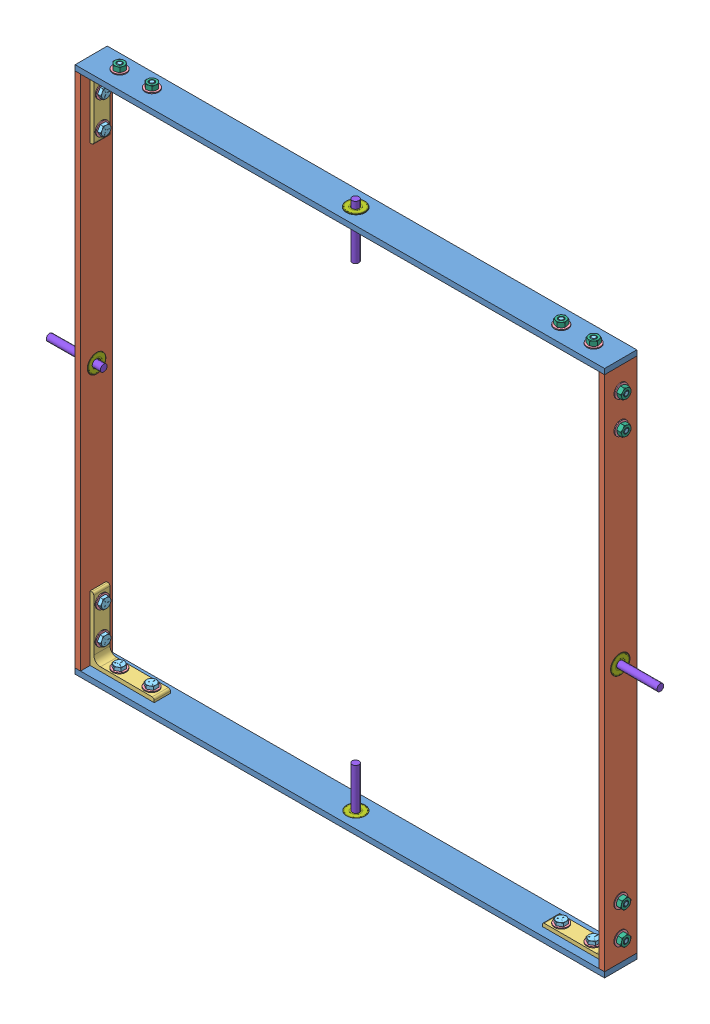
SolidWorks assembly OutR_22mm, configuration Default. Lengths in mm.
Overall size (717.82 639.44 40.05).
80 component instances, 8 part files, 23 mates.
Components (placement in the parent):
- OutR_L_22mm-1: OutR_L_22mm [Default] at (0.2194 -311.15 0.7559) x (0.999995 0 -0.003135) z (0.003135 0 0.999995) size (622.3 6.35 38.1)
- OutR_L_22mm-2: OutR_L_22mm [Default] at (0.2194 311.15 0.7559) x (-0.999995 0 0.003135) z (0.003135 0 0.999995) size (622.3 6.35 38.1)
- OutR_S_22mm-1: OutR_S_22mm [Default] at (-304.5791 0 1.7116) x (0 1 0) z (0.003135 0 0.999995) size (609.6 6.35 38.1)
- OutR_S_22mm-2: OutR_S_22mm [Default] at (305.0179 0 -0.1998) x (0 -1 0) z (0.003135 0 0.999995) size (609.6 6.35 38.1)
- Stand_Bracket_3in-1: Stand_Bracket_3in [8982K254] at (266.9181 266.7 -0.0803) x (0.999995 0 -0.003135) z (-0.003135 0 -0.999995) size (76.2 76.2 19.05)
- Stand_Bracket_3in-2: Stand_Bracket_3in [8982K254] at (-266.7 266.9181 -0.0803) x (0 0.999995 -0.003135) z (0 -0.003135 -0.999995) size (76.2 76.2 19.05)
- Stand_Bracket_3in-3: Stand_Bracket_3in [8982K254] at (-266.9181 -266.7 -0.0803) x (-0.999995 0 -0.003135) z (0.003135 0 -0.999995) size (76.2 76.2 19.05)
- Stand_Bracket_3in-4: Stand_Bracket_3in [8982K254] at (266.7 -266.9181 -0.0803) x (0 -0.999995 -0.003135) z (0 0.003135 -0.999995) size (76.2 76.2 19.05)
- 90107A029_316 Stainless Steel Washer-1: 90107A029_316 Stainless Steel Washer [90107A029] at (241.5182 298.9453 -0.0007) size (15.88 1.09 15.88)
- 92965A540_Black-Oxide Grade 5 Steel Hex Head Screws-1: 92965A540_Black-Oxide Grade 5 Steel Hex Head Screws [92965A540] at (241.5182 306.4859 -0.0007) x (0 1 0) z (-0.999784 0 0.020761) size (23.49 12.83 11.11)
- 95462A029_Medium-Strength Steel Hex Nut-1: 95462A029_Medium-Strength Steel Hex Nut [95462A029] at (241.5182 315.0203 -0.0007) x (0.295019 0 -0.955491) z (0 1 0) size (11.11 12.83 6.51)
- 90107A029_316 Stainless Steel Washer-2: 90107A029_316 Stainless Steel Washer [90107A029] at (241.5182 311.15 -0.0007) size (15.88 1.09 15.88)
- 90107A029_316 Stainless Steel Washer-3: 90107A029_316 Stainless Steel Washer [90107A029] at (279.618 311.15 -0.1201) size (15.88 1.09 15.88)
- 95462A029_Medium-Strength Steel Hex Nut-2: 95462A029_Medium-Strength Steel Hex Nut [95462A029] at (279.618 315.0203 -0.1201) x (0.295019 0 -0.955491) z (0 1 0) size (11.11 12.83 6.51)
- 92965A540_Black-Oxide Grade 5 Steel Hex Head Screws-2: 92965A540_Black-Oxide Grade 5 Steel Hex Head Screws [92965A540] at (279.618 306.4859 -0.1201) x (0 1 0) z (-0.999784 0 0.020761) size (23.49 12.83 11.11)
- 90107A029_316 Stainless Steel Washer-4: 90107A029_316 Stainless Steel Washer [90107A029] at (279.618 298.9453 -0.1201) size (15.88 1.09 15.88)
- 90107A029_316 Stainless Steel Washer-5: 90107A029_316 Stainless Steel Washer [90107A029] at (299.1632 241.3 -0.1814) x (0.00001 0.999995 0.003135) z (-0.003135 0.003135 -0.99999) size (15.88 1.09 15.88)
- 92965A540_Black-Oxide Grade 5 Steel Hex Head Screws-3: 92965A540_Black-Oxide Grade 5 Steel Hex Head Screws [92965A540] at (306.7038 241.3 -0.2051) x (0.999995 0 -0.003135) z (-0.000055 0.999845 -0.017626) size (23.49 12.83 11.11)
- 95462A029_Medium-Strength Steel Hex Nut-3: 95462A029_Medium-Strength Steel Hex Nut [95462A029] at (315.2392 241.3 -0.2318) x (-0.002993 0.298014 -0.954557) z (-0.999995 0 0.003135) size (11.11 12.83 6.51)
- 90107A029_316 Stainless Steel Washer-6: 90107A029_316 Stainless Steel Washer [90107A029] at (311.3679 241.3 -0.2197) x (0.00001 0.999995 0.003135) z (-0.003135 0.003135 -0.99999) size (15.88 1.09 15.88)
- 90107A029_316 Stainless Steel Washer-7: 90107A029_316 Stainless Steel Washer [90107A029] at (311.3679 279.4 -0.2197) x (0.00001 0.999995 0.003135) z (-0.003135 0.003135 -0.99999) size (15.88 1.09 15.88)
- 95462A029_Medium-Strength Steel Hex Nut-4: 95462A029_Medium-Strength Steel Hex Nut [95462A029] at (315.2392 279.4 -0.2318) x (-0.002993 0.298014 -0.954557) z (-0.999995 0 0.003135) size (11.11 12.83 6.51)
- 92965A540_Black-Oxide Grade 5 Steel Hex Head Screws-4: 92965A540_Black-Oxide Grade 5 Steel Hex Head Screws [92965A540] at (306.7038 279.4 -0.2051) x (0.999995 0 -0.003135) z (-0.000055 0.999845 -0.017626) size (23.49 12.83 11.11)
- 90107A029_316 Stainless Steel Washer-8: 90107A029_316 Stainless Steel Washer [90107A029] at (299.1632 279.4 -0.1814) x (0.00001 0.999995 0.003135) z (-0.003135 0.003135 -0.99999) size (15.88 1.09 15.88)
- 90107A029_316 Stainless Steel Washer-9: 90107A029_316 Stainless Steel Washer [90107A029] at (-241.3 299.1632 -0.1814) x (-0.999995 0.00001 0.003135) z (-0.003135 -0.003135 -0.99999) size (15.88 1.09 15.88)
- 90107A029_316 Stainless Steel Washer-10: 90107A029_316 Stainless Steel Washer [90107A029] at (-299.1632 -241.3 -0.1814) x (-0.00001 -0.999995 0.003135) z (0.003135 -0.003135 -0.99999) size (15.88 1.09 15.88)
- 90107A029_316 Stainless Steel Washer-11: 90107A029_316 Stainless Steel Washer [90107A029] at (241.3 -299.1632 -0.1814) x (0.999995 -0.00001 0.003135) z (0.003135 0.003135 -0.99999) size (15.88 1.09 15.88)
- 92965A540_Black-Oxide Grade 5 Steel Hex Head Screws-5: 92965A540_Black-Oxide Grade 5 Steel Hex Head Screws [92965A540] at (-241.3 306.7038 -0.2051) x (0 0.999995 -0.003135) z (-0.999845 -0.000055 -0.017626) size (23.49 12.83 11.11)
- 92965A540_Black-Oxide Grade 5 Steel Hex Head Screws-6: 92965A540_Black-Oxide Grade 5 Steel Hex Head Screws [92965A540] at (-306.7038 -241.3 -0.2051) x (-0.999995 0 -0.003135) z (0.000055 -0.999845 -0.017626) size (23.49 12.83 11.11)
- 92965A540_Black-Oxide Grade 5 Steel Hex Head Screws-7: 92965A540_Black-Oxide Grade 5 Steel Hex Head Screws [92965A540] at (241.3 -306.7038 -0.2051) x (0 -0.999995 -0.003135) z (0.999845 0.000055 -0.017626) size (23.49 12.83 11.11)
- 95462A029_Medium-Strength Steel Hex Nut-5: 95462A029_Medium-Strength Steel Hex Nut [95462A029] at (-241.3 315.2392 -0.2318) x (-0.298014 -0.002993 -0.954557) z (0 -0.999995 0.003135) size (11.11 12.83 6.51)
- 95462A029_Medium-Strength Steel Hex Nut-6: 95462A029_Medium-Strength Steel Hex Nut [95462A029] at (-315.2392 -241.3 -0.2318) x (0.002993 -0.298014 -0.954557) z (0.999995 0 0.003135) size (11.11 12.83 6.51)
- 95462A029_Medium-Strength Steel Hex Nut-7: 95462A029_Medium-Strength Steel Hex Nut [95462A029] at (241.3 -315.2392 -0.2318) x (0.298014 0.002993 -0.954557) z (0 0.999995 0.003135) size (11.11 12.83 6.51)
- 90107A029_316 Stainless Steel Washer-12: 90107A029_316 Stainless Steel Washer [90107A029] at (-241.3 311.3679 -0.2197) x (-0.999995 0.00001 0.003135) z (-0.003135 -0.003135 -0.99999) size (15.88 1.09 15.88)
- 90107A029_316 Stainless Steel Washer-13: 90107A029_316 Stainless Steel Washer [90107A029] at (-311.3679 -241.3 -0.2197) x (-0.00001 -0.999995 0.003135) z (0.003135 -0.003135 -0.99999) size (15.88 1.09 15.88)
- 90107A029_316 Stainless Steel Washer-14: 90107A029_316 Stainless Steel Washer [90107A029] at (241.3 -311.3679 -0.2197) x (0.999995 -0.00001 0.003135) z (0.003135 0.003135 -0.99999) size (15.88 1.09 15.88)
- 90107A029_316 Stainless Steel Washer-15: 90107A029_316 Stainless Steel Washer [90107A029] at (-279.4 311.3679 -0.2197) x (-0.999995 0.00001 0.003135) z (-0.003135 -0.003135 -0.99999) size (15.88 1.09 15.88)
- 90107A029_316 Stainless Steel Washer-16: 90107A029_316 Stainless Steel Washer [90107A029] at (-311.3679 -279.4 -0.2197) x (-0.00001 -0.999995 0.003135) z (0.003135 -0.003135 -0.99999) size (15.88 1.09 15.88)
- 90107A029_316 Stainless Steel Washer-17: 90107A029_316 Stainless Steel Washer [90107A029] at (279.4 -311.3679 -0.2197) x (0.999995 -0.00001 0.003135) z (0.003135 0.003135 -0.99999) size (15.88 1.09 15.88)
- 95462A029_Medium-Strength Steel Hex Nut-8: 95462A029_Medium-Strength Steel Hex Nut [95462A029] at (-279.4 315.2392 -0.2318) x (-0.298014 -0.002993 -0.954557) z (0 -0.999995 0.003135) size (11.11 12.83 6.51)
- 95462A029_Medium-Strength Steel Hex Nut-9: 95462A029_Medium-Strength Steel Hex Nut [95462A029] at (-315.2392 -279.4 -0.2318) x (0.002993 -0.298014 -0.954557) z (0.999995 0 0.003135) size (11.11 12.83 6.51)
- 95462A029_Medium-Strength Steel Hex Nut-10: 95462A029_Medium-Strength Steel Hex Nut [95462A029] at (279.4 -315.2392 -0.2318) x (0.298014 0.002993 -0.954557) z (0 0.999995 0.003135) size (11.11 12.83 6.51)
- 92965A540_Black-Oxide Grade 5 Steel Hex Head Screws-8: 92965A540_Black-Oxide Grade 5 Steel Hex Head Screws [92965A540] at (-279.4 306.7038 -0.2051) x (0 0.999995 -0.003135) z (-0.999845 -0.000055 -0.017626) size (23.49 12.83 11.11)
- 92965A540_Black-Oxide Grade 5 Steel Hex Head Screws-9: 92965A540_Black-Oxide Grade 5 Steel Hex Head Screws [92965A540] at (-306.7038 -279.4 -0.2051) x (-0.999995 0 -0.003135) z (0.000055 -0.999845 -0.017626) size (23.49 12.83 11.11)
- 92965A540_Black-Oxide Grade 5 Steel Hex Head Screws-10: 92965A540_Black-Oxide Grade 5 Steel Hex Head Screws [92965A540] at (279.4 -306.7038 -0.2051) x (0 -0.999995 -0.003135) z (0.999845 0.000055 -0.017626) size (23.49 12.83 11.11)
- 90107A029_316 Stainless Steel Washer-18: 90107A029_316 Stainless Steel Washer [90107A029] at (-279.4 299.1632 -0.1814) x (-0.999995 0.00001 0.003135) z (-0.003135 -0.003135 -0.99999) size (15.88 1.09 15.88)
- 90107A029_316 Stainless Steel Washer-19: 90107A029_316 Stainless Steel Washer [90107A029] at (-299.1632 -279.4 -0.1814) x (-0.00001 -0.999995 0.003135) z (0.003135 -0.003135 -0.99999) size (15.88 1.09 15.88)
- 90107A029_316 Stainless Steel Washer-20: 90107A029_316 Stainless Steel Washer [90107A029] at (279.4 -299.1632 -0.1814) x (0.999995 -0.00001 0.003135) z (0.003135 0.003135 -0.99999) size (15.88 1.09 15.88)
- 90107A029_316 Stainless Steel Washer-21: 90107A029_316 Stainless Steel Washer [90107A029] at (-311.15 241.5182 -0.0007) x (0 1 0) z (0 0 1) size (15.88 1.09 15.88)
- 90107A029_316 Stainless Steel Washer-22: 90107A029_316 Stainless Steel Washer [90107A029] at (-241.5182 -311.15 -0.0007) x (-1 0 0) z (0 0 1) size (15.88 1.09 15.88)
- 90107A029_316 Stainless Steel Washer-23: 90107A029_316 Stainless Steel Washer [90107A029] at (311.15 -241.5182 -0.0007) x (0 -1 0) z (0 0 1) size (15.88 1.09 15.88)
- 95462A029_Medium-Strength Steel Hex Nut-11: 95462A029_Medium-Strength Steel Hex Nut [95462A029] at (-315.0203 241.5182 -0.0007) x (0 0.295019 -0.955491) z (-1 0 0) size (11.11 12.83 6.51)
- 95462A029_Medium-Strength Steel Hex Nut-12: 95462A029_Medium-Strength Steel Hex Nut [95462A029] at (-241.5182 -315.0203 -0.0007) x (-0.295019 0 -0.955491) z (0 -1 0) size (11.11 12.83 6.51)
- 95462A029_Medium-Strength Steel Hex Nut-13: 95462A029_Medium-Strength Steel Hex Nut [95462A029] at (315.0203 -241.5182 -0.0007) x (0 -0.295019 -0.955491) z (1 0 0) size (11.11 12.83 6.51)
- 92965A540_Black-Oxide Grade 5 Steel Hex Head Screws-11: 92965A540_Black-Oxide Grade 5 Steel Hex Head Screws [92965A540] at (-306.4859 241.5182 -0.0007) x (-1 0 0) z (0 -0.999784 0.020761) size (23.49 12.83 11.11)
- 92965A540_Black-Oxide Grade 5 Steel Hex Head Screws-12: 92965A540_Black-Oxide Grade 5 Steel Hex Head Screws [92965A540] at (-241.5182 -306.4859 -0.0007) x (0 -1 0) z (0.999784 0 0.020761) size (23.49 12.83 11.11)
- 92965A540_Black-Oxide Grade 5 Steel Hex Head Screws-13: 92965A540_Black-Oxide Grade 5 Steel Hex Head Screws [92965A540] at (306.4859 -241.5182 -0.0007) x (1 0 0) z (0 0.999784 0.020761) size (23.49 12.83 11.11)
- 90107A029_316 Stainless Steel Washer-24: 90107A029_316 Stainless Steel Washer [90107A029] at (-298.9453 241.5182 -0.0007) x (0 1 0) z (0 0 1) size (15.88 1.09 15.88)
- 90107A029_316 Stainless Steel Washer-25: 90107A029_316 Stainless Steel Washer [90107A029] at (-241.5182 -298.9453 -0.0007) x (-1 0 0) z (0 0 1) size (15.88 1.09 15.88)
- 90107A029_316 Stainless Steel Washer-26: 90107A029_316 Stainless Steel Washer [90107A029] at (298.9453 -241.5182 -0.0007) x (0 -1 0) z (0 0 1) size (15.88 1.09 15.88)
- 90107A029_316 Stainless Steel Washer-27: 90107A029_316 Stainless Steel Washer [90107A029] at (-311.15 279.618 -0.1201) x (0 1 0) z (0 0 1) size (15.88 1.09 15.88)
- 90107A029_316 Stainless Steel Washer-28: 90107A029_316 Stainless Steel Washer [90107A029] at (-279.618 -311.15 -0.1201) x (-1 0 0) z (0 0 1) size (15.88 1.09 15.88)
- 90107A029_316 Stainless Steel Washer-29: 90107A029_316 Stainless Steel Washer [90107A029] at (311.15 -279.618 -0.1201) x (0 -1 0) z (0 0 1) size (15.88 1.09 15.88)
- 95462A029_Medium-Strength Steel Hex Nut-14: 95462A029_Medium-Strength Steel Hex Nut [95462A029] at (-315.0203 279.618 -0.1201) x (0 0.295019 -0.955491) z (-1 0 0) size (11.11 12.83 6.51)
- 95462A029_Medium-Strength Steel Hex Nut-15: 95462A029_Medium-Strength Steel Hex Nut [95462A029] at (-279.618 -315.0203 -0.1201) x (-0.295019 0 -0.955491) z (0 -1 0) size (11.11 12.83 6.51)
- 95462A029_Medium-Strength Steel Hex Nut-16: 95462A029_Medium-Strength Steel Hex Nut [95462A029] at (315.0203 -279.618 -0.1201) x (0 -0.295019 -0.955491) z (1 0 0) size (11.11 12.83 6.51)
- 92965A540_Black-Oxide Grade 5 Steel Hex Head Screws-14: 92965A540_Black-Oxide Grade 5 Steel Hex Head Screws [92965A540] at (-306.4859 279.618 -0.1201) x (-1 0 0) z (0 -0.999784 0.020761) size (23.49 12.83 11.11)
- 92965A540_Black-Oxide Grade 5 Steel Hex Head Screws-15: 92965A540_Black-Oxide Grade 5 Steel Hex Head Screws [92965A540] at (-279.618 -306.4859 -0.1201) x (0 -1 0) z (0.999784 0 0.020761) size (23.49 12.83 11.11)
- 92965A540_Black-Oxide Grade 5 Steel Hex Head Screws-16: 92965A540_Black-Oxide Grade 5 Steel Hex Head Screws [92965A540] at (306.4859 -279.618 -0.1201) x (1 0 0) z (0 0.999784 0.020761) size (23.49 12.83 11.11)
- 90107A029_316 Stainless Steel Washer-30: 90107A029_316 Stainless Steel Washer [90107A029] at (-298.9453 279.618 -0.1201) x (0 1 0) z (0 0 1) size (15.88 1.09 15.88)
- 90107A029_316 Stainless Steel Washer-31: 90107A029_316 Stainless Steel Washer [90107A029] at (-279.618 -298.9453 -0.1201) x (-1 0 0) z (0 0 1) size (15.88 1.09 15.88)
- 90107A029_316 Stainless Steel Washer-32: 90107A029_316 Stainless Steel Washer [90107A029] at (298.9453 -279.618 -0.1201) x (0 -1 0) z (0 0 1) size (15.88 1.09 15.88)
- 4668K133_Permanently Lubricated Stainless Steel Ball Bearing-1: 4668K133_Permanently Lubricated Stainless Steel Ball Bearing [4668K133] at (0.2194 -308.3 0.7559) x (1 0 0) z (0 1 0) size (22 22 7)
- 4668K133_Permanently Lubricated Stainless Steel Ball Bearing-2: 4668K133_Permanently Lubricated Stainless Steel Ball Bearing [4668K133] at (308.3 0.2194 0.7559) x (0 1 0) z (-1 0 0) size (22 22 7)
- 4668K133_Permanently Lubricated Stainless Steel Ball Bearing-3: 4668K133_Permanently Lubricated Stainless Steel Ball Bearing [4668K133] at (-0.2194 308.3 0.7559) x (-1 0 0) z (0 -1 0) size (22 22 7)
- 4668K133_Permanently Lubricated Stainless Steel Ball Bearing-4: 4668K133_Permanently Lubricated Stainless Steel Ball Bearing [4668K133] at (-308.3 -0.2194 0.7559) x (0 -1 0) z (1 0 0) size (22 22 7)
- StandShaft-6: StandShaft [Default] at (359.1182 0.2194 0.7559) x (0 -0.204961 -0.97877) z (0 0.97877 -0.204961) size (8 63.5 8)
- StandShaft-7: StandShaft [Default] at (-358.6724 0.2194 3.0065) x (-0.006138 -0.204961 -0.978751) z (0.001285 -0.97877 0.204957) size (8 63.5 8)
- StandShaft-8: StandShaft [Default] at (-0.2194 319.7177 0.7559) x (-0.032217 0 0.999481) z (0.999481 0 0.032217) size (8 63.5 8)
- StandShaft-9: StandShaft [Default] at (-0.2194 -319.7177 0.7559) x (-0.032217 0 0.999481) z (-0.999481 0 -0.032217) size (8 63.5 8)
Mates (geometry in assembly coordinates):
- Coincident6: coincident aligned: plane of OutR_L_22mm-2 through (311.4276 304.8 18.8302) normal (0.003135 0 0.999995); plane of OutR_S_22mm-2 through (311.4276 304.8 18.8302) normal (0.003135 0 0.999995)
- Coincident12: coincident aligned: plane of OutR_L_22mm-1 through (-310.8694 -304.8 20.7814) normal (0.003135 0 0.999995); plane of OutR_S_22mm-2 through (311.4276 304.8 18.8302) normal (0.003135 0 0.999995)
- Coincident14: coincident aligned: plane of OutR_L_22mm-1 through (-310.8694 -304.8 20.7814) normal (0.003135 0 0.999995); plane of OutR_S_22mm-1 through (-310.8694 -304.8 20.7814) normal (0.003135 0 0.999995)
- Coincident15: coincident anti-aligned: plane of OutR_L_22mm-1 through (0.2194 -304.8 0.7559) normal (0 1 0); plane of OutR_S_22mm-1 through (-310.8694 -304.8 20.7814) normal (0 -1 0)
- Coincident16: coincident aligned: plane of OutR_L_22mm-1 through (-310.9888 -304.8 -17.3184) normal (-0.999995 0 0.003135); plane of OutR_S_22mm-1 through (-310.9291 0 1.7315) normal (-0.999995 0 0.003135)
- Coincident17: coincident aligned: plane of OutR_L_22mm-2 through (-310.9888 304.8 -17.3184) normal (-0.999995 0 0.003135); plane of OutR_S_22mm-1 through (-310.9291 0 1.7315) normal (-0.999995 0 0.003135)
- Coincident18: coincident anti-aligned: plane of OutR_L_22mm-2 through (0.2194 304.8 0.7559) normal (0 -1 0); plane of OutR_S_22mm-1 through (-310.8694 304.8 20.7814) normal (0 1 0)
- Coincident19: coincident anti-aligned: plane of OutR_L_22mm-2 through (0.2194 304.8 0.7559) normal (0 -1 0); plane of OutR_S_22mm-2 through (311.4276 304.8 18.8302) normal (0 1 0)
- Coincident20: coincident aligned: plane of OutR_L_22mm-2 through (311.3081 304.8 -19.2696) normal (0.999995 0 -0.003135); plane of OutR_S_22mm-2 through (311.3679 0 -0.2197) normal (0.999995 0 -0.003135)
- Concentric1: concentric anti-aligned: cylinder of Stand_Bracket_3in-1 through (300.2554 241.3 -0.1849) axis (-0.999995 0 0.003135) radius 3.2639; cylinder of OutR_S_22mm-2 through (311.3679 241.3 -0.2197) axis (0.999995 0 -0.003135) radius 3.2639
- Concentric3: concentric aligned: cylinder of OutR_L_22mm-2 through (241.5182 304.8 -0.0007) axis (0 -1 0) radius 3.2639; cylinder of Stand_Bracket_3in-1 through (241.5182 300.0375 -0.0007) axis (0 -1 0) radius 3.2639
- Coincident21: coincident anti-aligned: axis of 90107A029_316 Stainless Steel Washer-1 through (1.0922 241.5182 300.0375) axis (-0.000001 0 -1); line of 92965A540_Black-Oxide Grade 5 Steel Hex Head Screws-1 through (241.5182 298.9453 -0.0007) axis (0 1 0)
- Coincident22: coincident anti-aligned: line of 92965A540_Black-Oxide Grade 5 Steel Hex Head Screws-1 through (241.5182 298.9453 -0.0007) axis (0 1 0); line of 95462A029_Medium-Strength Steel Hex Nut-1 through (241.5182 317.7985 -0.0007) axis (0 -1 0)
- Coincident23: coincident anti-aligned: line of 92965A540_Black-Oxide Grade 5 Steel Hex Head Screws-1 through (241.5182 298.9453 -0.0007) axis (0 1 0); line of 90107A029_316 Stainless Steel Washer-2 through (1.0922 241.5182 312.2422) axis (-0.000001 0 -1)
- Coincident24: coincident anti-aligned: plane of Stand_Bracket_3in-1 through (292.3008 300.0375 -9.685) normal (0 -1 0); plane of 90107A029_316 Stainless Steel Washer-1 through (241.5182 300.0375 -0.0007) normal (0 1 0)
- Coincident25: coincident aligned: line of Stand_Bracket_3in-1 through (241.5182 304.8 -0.0007) axis (0 -1 0); line of 90107A029_316 Stainless Steel Washer-1 through (1.0922 241.5182 300.0375) axis (-0.000001 0 -1)
- Coincident26: coincident anti-aligned: plane of 90107A029_316 Stainless Steel Washer-1 through (241.5182 298.9453 -0.0007) normal (0 -1 0); plane of 92965A540_Black-Oxide Grade 5 Steel Hex Head Screws-1 through (235.8966 298.9453 -3.0925) normal (0 1 0)
- Coincident27: coincident anti-aligned: plane of OutR_L_22mm-2 through (0.2194 311.15 0.7559) normal (0 1 0); plane of 90107A029_316 Stainless Steel Washer-2 through (241.5182 311.15 -0.0007) normal (0 -1 0)
- Coincident28: coincident anti-aligned: plane of 95462A029_Medium-Strength Steel Hex Nut-1 through (236.8139 312.2422 4.3619) normal (0 -1 0); plane of 90107A029_316 Stainless Steel Washer-2 through (241.5182 312.2422 -0.0007) normal (0 1 0)
- Concentric4: concentric anti-aligned: cylinder of OutR_L_22mm-1 through (0.2194 -304.8 0.7559) axis (0 -1 0) radius 11; cylinder of 4668K133_Permanently Lubricated Stainless Steel Ball Bearing-1 through (0.2194 -304.8 0.7559) axis (0 1 0) radius 11
- Coincident29: coincident aligned: plane of OutR_L_22mm-1 through (0.2194 -304.8 0.7559) normal (0 1 0); plane of 4668K133_Permanently Lubricated Stainless Steel Ball Bearing-1 through (0.2194 -304.8 0.7559) normal (0 1 0)
- Concentric6: concentric anti-aligned: cylinder of 4668K133_Permanently Lubricated Stainless Steel Ball Bearing-2 through (304.8 0.2194 0.7559) axis (-1 0 0) radius 4; cylinder of StandShaft-6 through (295.6182 0.2194 0.7559) axis (1 0 0) radius 4
- Concentric7: concentric anti-aligned: cylinder of 4668K133_Permanently Lubricated Stainless Steel Ball Bearing-3 through (-0.2194 304.8 0.7559) axis (0 -1 0) radius 4; cylinder of StandShaft-8 through (-0.2194 256.2177 0.7559) axis (0 1 0) radius 4
